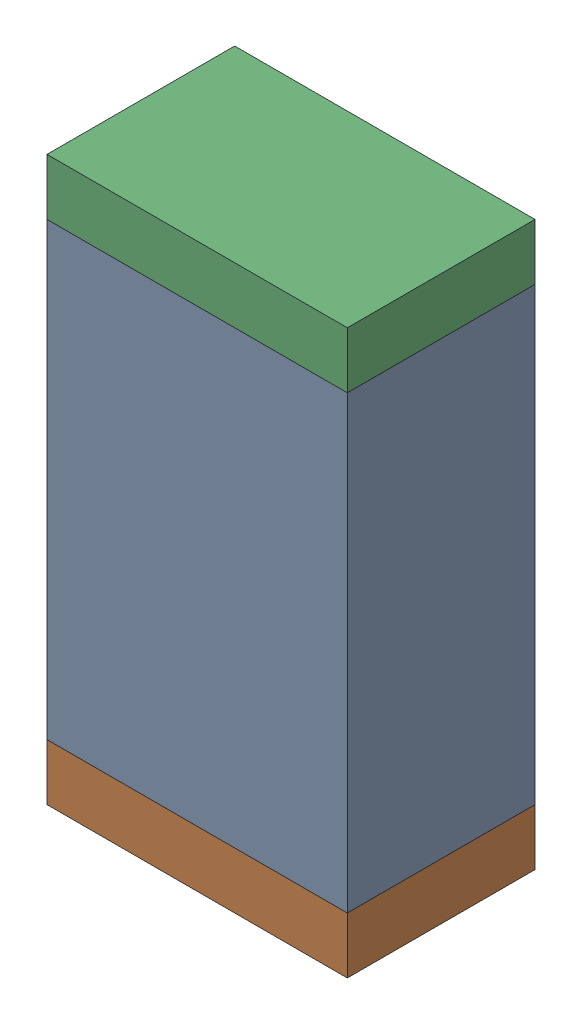
SolidWorks assembly L2, configuration Default. Lengths in mm.
Overall size (0.8 1.5 0.5).
6 component instances, 2 part files, 0 mates.
Components (placement in the parent):
- 810156976-1: 810156976 [Default] at (114.7 8.1 0) size (0.8 1.2 0.5)
  - Extruded_6-1: Extruded_6 [Default] at origin size (0.8 1.2 0.5)
- 810156592-1: 810156592 [Default] at (114.7 7.425 0) size (0.8 0.15 0.5)
  - Extruded_7-1: Extruded_7 [Default] at origin size (0.8 0.15 0.5)
- 810156592-2: 810156592 [Default] at (114.7 8.775 0) size (0.8 0.15 0.5)
  - Extruded_7-1: Extruded_7 [Default] at origin size (0.8 0.15 0.5)
